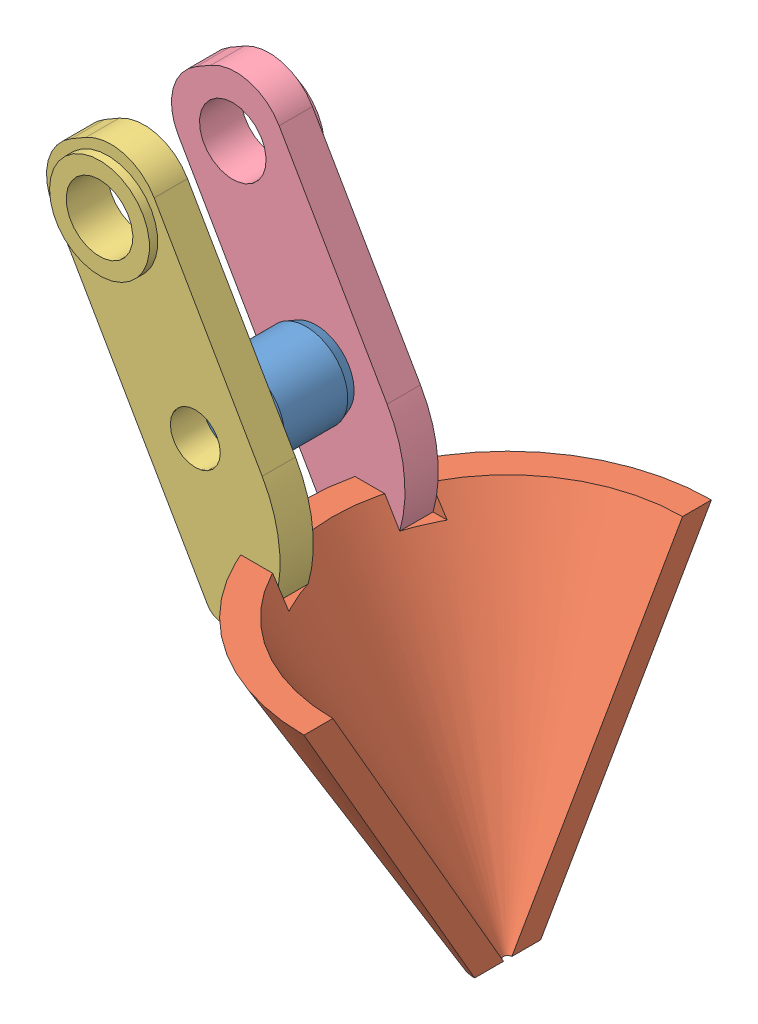
SolidWorks assembly 管门机构, configuration 默认. Lengths in mm.
Overall size (30.19 36.37 24.46).
4 component instances, 4 part files, 2 mates.
Components (placement in the parent):
- 卷制轴套3×5×5-1: 卷制轴套3×5×5 [3×5×3] at (-14 9 2.5) x (0 0 -1) z (-0.194187 0.980965 0) size (5 5 5)
- pipe_gate-1: pipe_gate [默认] at origin size (12.23 17.75 24.46)
- pipe_gate_lever-1: pipe_gate_lever [默认] at (0 0 40.0025) size (11.77 22.05 2.75)
- 镜向pipe_gate_lever-4: 镜向pipe_gate_lever [默认] at (0 0 -40.0025) size (11.77 22.05 2.75)
Mates (geometry in assembly coordinates):
- 同心1: concentric: 卷制轴套3×5×5-1, pipe_gate_lever-1
- 宽度1: width: 镜向pipe_gate_lever-4, pipe_gate_lever-1, 卷制轴套3×5×5-1
